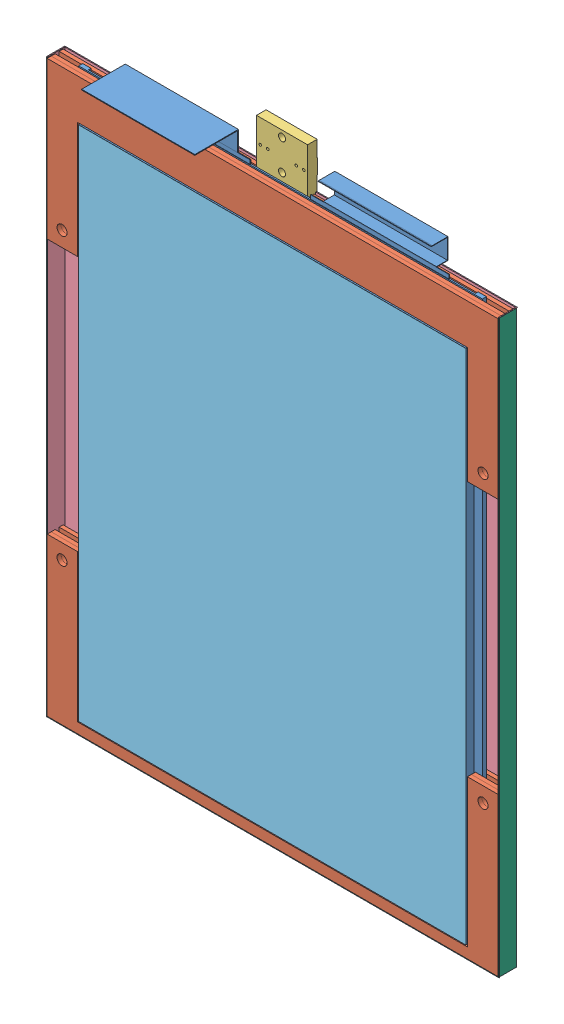
SolidWorks assembly Positive End Module, configuration Default. Lengths in mm.
Overall size (179.74 245.1 14.97).
8 component instances, 6 part files, 23 mates.
Components (placement in the parent):
- Cell Tab Config B Positive End-1: Cell Tab Config B Positive End [Default<As Machined>] at (47.682 121.9858 173.2819) size (160.6 236.86 14.97)
- Repeating Frame Outer-1: Repeating Frame Outer [Default] at (47.682 115.7358 173.5819) size (179.3 226.63 1.59)
- Repeating Frame Outer-2: Repeating Frame Outer [Default] at (47.682 115.7358 175.1694) size (179.3 226.63 1.59)
- Repeating Frame Outer-3: Repeating Frame Outer [Default] at (47.682 115.7358 170.3784) size (179.3 226.63 1.59)
- Cell Board End-1: Cell Board End [Default] at (47.682 240.5308 169.1719) x (-1 0 0) z (0 0 1) size (20.32 25.4 3.91)
- Insulation Film Half-1: Insulation Film Half [Default] at (47.682 121.8215 169.6633) size (179.74 227.22 7.27)
- Insulation Film End-1: Insulation Film End [Default] at (47.682 115.7358 176.8319) size (154 205.5 0.07)
- Heat Sink Half-1: Heat Sink Half [Default] at (47.682 121.7872 169.5109) size (179.74 227.15 7.2)
Mates (geometry in assembly coordinates):
- Coincident4: coincident anti-aligned: plane of Cell Board End-1 through (47.682 240.5308 172.9819) normal (0 0 1); plane of Cell Tab Config B Positive End-1 through (47.682 121.9858 172.9819) normal (0 0 -1)
- Distance1: distance = 0.6 mm: line of Cell Tab Config B Positive End-1 through (124.682 235.4858 172.9819) axis (-1 0 0); line of Cell Board End-1 through (37.522 236.0858 172.9819) axis (1 0 0)
- Concentric1: concentric aligned: circle of Heat Sink Half-1; circle of Insulation Film Half-1
- Concentric2: concentric aligned: circle of Heat Sink Half-1; cylinder of Repeating Frame Outer-1 through (131.402 178.7658 175.1694) axis (0 0 -1) radius 2
- Concentric3: concentric aligned: circle of Heat Sink Half-1; cylinder of Repeating Frame Outer-3 through (131.402 178.7658 171.9659) axis (0 0 -1) radius 2
- Concentric4: concentric aligned: circle of Heat Sink Half-1; cylinder of Repeating Frame Outer-2 through (131.402 178.7658 176.7569) axis (0 0 -1) radius 2
- Concentric5: concentric aligned: circle of Heat Sink Half-1; circle of Insulation Film Half-1
- Concentric6: concentric anti-aligned: circle of Heat Sink Half-1; cylinder of Repeating Frame Outer-2 through (-36.038 178.7658 176.7569) axis (0 0 -1) radius 2
- Concentric7: concentric aligned: circle of Heat Sink Half-1; circle of Repeating Frame Outer-3
- Concentric8: concentric aligned: circle of Heat Sink Half-1; circle of Repeating Frame Outer-2
- Concentric9: concentric aligned: circle of Heat Sink Half-1; cylinder of Repeating Frame Outer-2 through (131.402 178.7658 176.7569) axis (0 0 -1) radius 2
- Coincident20: coincident anti-aligned: plane of Heat Sink Half-1 through (47.682 121.7872 169.6633) normal (0 0 1); plane of Insulation Film Half-1 through (47.682 121.8215 169.6633) normal (0 0 -1)
- Coincident24: coincident anti-aligned: plane of Cell Tab Config B Positive End-1 through (47.682 121.9858 176.8319) normal (0 0 1); plane of Insulation Film End-1 through (47.682 115.7358 176.8319) normal (0 0 -1)
- Coincident25: coincident aligned: plane of Cell Tab Config B Positive End-1 through (47.682 121.9858 173.2819) normal (1 0 0); plane of Insulation Film End-1 through (47.682 115.7358 176.8319) normal (1 0 0)
- Coincident26: coincident aligned: plane of Cell Tab Config B Positive End-1 through (-29.318 218.4858 169.7319) normal (0 1 0); plane of Insulation Film End-1 through (-29.318 218.4858 176.9005) normal (0 1 0)
- Coincident27: coincident aligned: plane of Cell Tab Config B Positive End-1 through (47.682 121.9858 173.2819) normal (1 0 0); plane of Repeating Frame Outer-1 through (47.682 115.7358 173.5819) normal (1 0 0)
- Distance2: distance = 0.5 mm anti-aligned: plane of Cell Tab Config B Positive End-1 through (-29.318 12.9858 169.7319) normal (0 -1 0); plane of Repeating Frame Outer-2 through (47.682 12.4858 176.7569) normal (0 1 0)
- Coincident30: coincident anti-aligned: plane of Cell Tab Config B Positive End-1 through (47.682 121.9858 169.7319) normal (0 0 -1); plane of Insulation Film Half-1 through (47.682 121.8215 169.7319) normal (0 0 1)
- Coincident31: coincident anti-aligned: plane of Cell Board End-1; plane of Cell Tab Config B Positive End-1 through (47.682 121.9858 173.2819) normal (1 0 0)
- Concentric10: concentric aligned: cylinder of Repeating Frame Outer-1 through (-36.038 178.7658 175.1694) axis (0 0 -1) radius 2; cylinder of Heat Sink Half-1 through (-36.038 178.7658 169.6633) axis (0 0 -1) radius 2
- Coincident32: coincident anti-aligned: plane of Cell Tab Config B Positive End-1 through (47.682 121.9858 171.9659) normal (0 0 -1); plane of Repeating Frame Outer-3 through (47.682 115.7358 171.9659) normal (0 0 1)
- Coincident33: coincident anti-aligned: plane of Cell Tab Config B Positive End-1 through (47.682 121.9858 173.5819) normal (0 0 1); plane of Repeating Frame Outer-1 through (47.682 115.7358 173.5819) normal (0 0 -1)
- Coincident34: coincident anti-aligned: plane of Repeating Frame Outer-1 through (47.682 115.7358 175.1694) normal (0 0 1); plane of Repeating Frame Outer-2 through (47.682 115.7358 175.1694) normal (0 0 -1)
